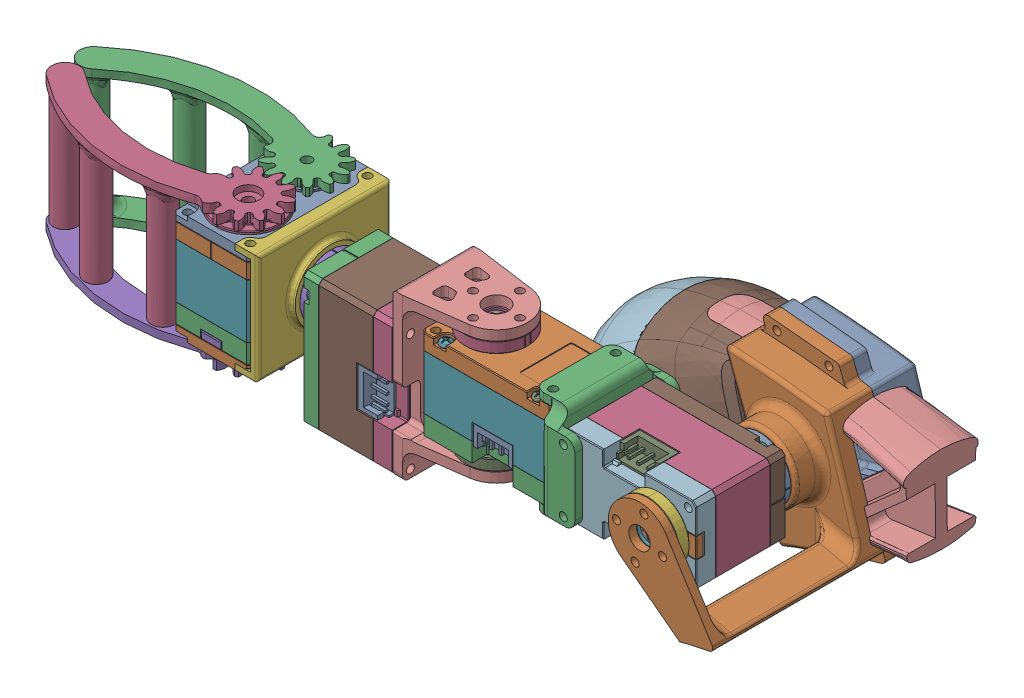
SolidWorks assembly loco-manipulator_left_urdf, configuration Default. Lengths in mm.
Overall size (198.32 72.36 70.91).
5 component instances, 5 part files, 13 mates.
Components (placement in the parent):
- link_1_left-1: link_1_left [Default] at origin size (36.26 44.35 61)
- link_2_left-1: link_2_left [Default] at (-272.1387 -81.5409 106.5) x (0 1 0) z (0 0 -1) size (29.02 72.1 29.02)
- link_3-1: link_3 [Default] at (-339.2387 -81.5409 114.5) x (0 0 -1) z (1 0 0) size (20 41.5 50.52)
- gripper-1: gripper [Default] at (-381.2387 -73.5409 122) x (-1 0 0) z (0 1 0) size (67.06 34.46 34.6)
- calf_left-1: calf_left [Default] at (-163.1832 -115.6303 81.5) x (-0.324223 0.945981 0) z (0.945981 0.324223 0) size (46.46 40.9 87.61)
Mates (geometry in assembly coordinates):
- Coincident1: coincident anti-aligned: plane of link_1_left-1 through (-272.1387 -81.5409 100) normal (0 0 1); plane of link_2_left-1 through (-272.1387 -81.5409 100) normal (0 0 -1)
- Concentric1: concentric anti-aligned: cylinder of link_1_left-1 through (-272.1387 -81.5409 70) axis (0 0 1) radius 3.25; cylinder of link_2_left-1 through (-272.1387 -81.5409 102.9) axis (0 0 -1) radius 8
- Parallel1: parallel aligned: plane of link_2_left-1 through (-296.6387 -71.5409 106.5) normal (0 1 0)
- Coincident3: coincident anti-aligned: plane of link_2_left-1 through (-325.2387 -67.0409 114.5) normal (0 1 0); plane of link_3-1 through (-325.2387 -67.0409 114.5) normal (0 -1 0)
- Concentric2: concentric aligned: cylinder of link_2_left-1 through (-325.2387 -69.9409 114.5) axis (0 1 0) radius 8; cylinder of link_3-1 through (-325.2387 -67.0409 114.5) axis (0 1 0) radius 3
- Coincident4: coincident aligned: plane of link_2_left-1 through (-334.7387 -73.5409 124.5) normal (0 0 1); plane of link_3-1 through (-361.2387 -106.0409 124.5) normal (0 0 1)
- Coincident5: coincident: plane of link_3-1 through (-367.7387 -81.5409 114.5) normal (-1 0 0); plane of gripper-1 through (-367.7387 -81.5409 114.5) normal (1 0 0)
- Concentric3: concentric: cylinder of link_3-1 through (-364.8387 -81.5409 114.5) axis (-1 0 0) radius 8; cylinder of gripper-1 through (-361.2387 -81.5409 114.5) axis (-1 0 0) radius 3.5
- Parallel2: parallel aligned: plane of link_3-1 through (-361.2387 -72.0409 124.5) normal (0 1 0); plane of gripper-1 through (-381.2387 -67.5409 114.5) normal (0 1 0)
- Width1: width: plane of calf_left-1 through (-231.0335 -90.7427 80) normal (0 0 -1); plane of calf_left-1 through (-231.0628 -90.7591 83) normal (0 0 1); plane of link_1_left-1 through (0 0 78) normal (0 0 -1); plane of link_1_left-1 through (0 0 85) normal (0 0 1)
- Angle1: planar angle = 0.29147 rad: plane of link_1_left-1 through (-258.4049 -80.3922 51.5) normal (0.954857 0.297065 0); plane of calf_left-1 through (-243.6499 -161.1426 63) normal (0.999949 0.010147 0)
- Distance1: distance = 15.47 mm: point of calf_left-1; plane of link_1_left-1 through (-258.4049 -80.3922 51.5) normal (0.954857 0.297065 0)
- Distance2: distance = 24.83 mm: point of calf_left-1; plane of link_1_left-1 through (7.2264 -24.5054 78) normal (0.282848 -0.959165 0)
